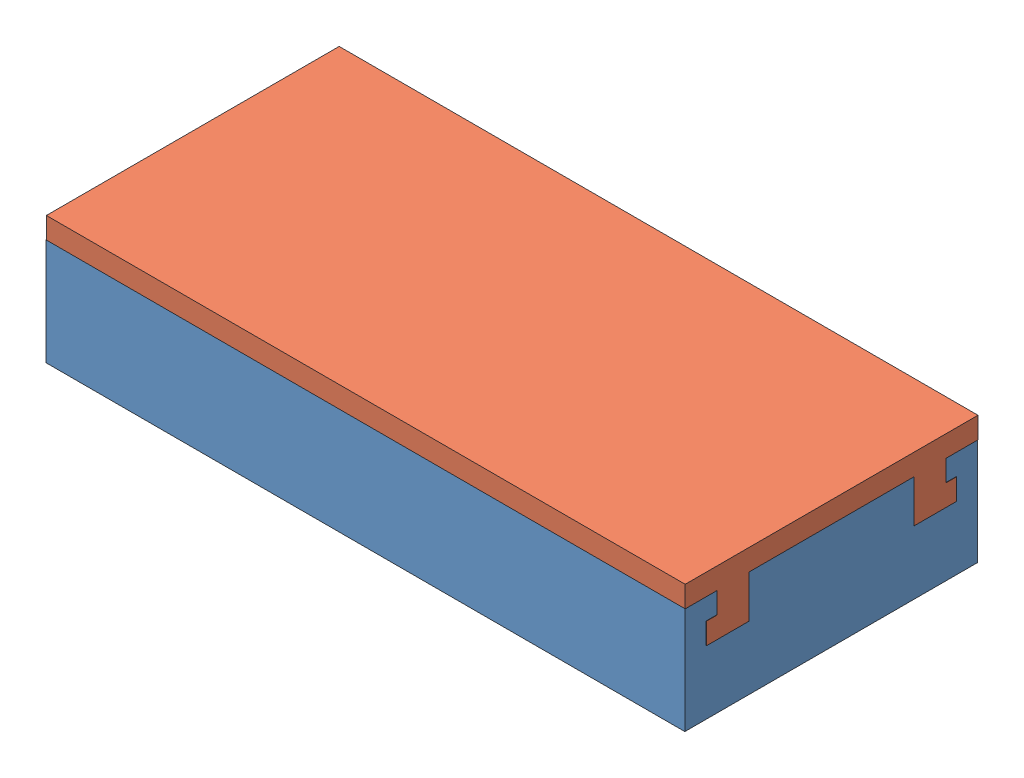
SolidWorks assembly Lighter_Asm, configuration Default. Lengths in mm.
Overall size (76.24 15.24 34.93).
2 component instances, 2 part files, 2 mates.
Components (placement in the parent):
- Lighter_housing-1: Lighter_housing [Default] at (-65.4269 20.9842 3.168) size (76.2 12.7 34.92)
- Lighter_lid-1: Lighter_lid [Default] at (-53.2421 36.2242 10.7981) x (-1 0 0) z (0 0 1) size (76.2 7.62 34.93)
Mates (geometry in assembly coordinates):
- Coincident3: coincident anti-aligned: plane of Lighter_housing-1 through (-16.9696 28.6042 -4.4335) normal (0 1 0); plane of Lighter_lid-1 through (-53.2421 28.6042 10.7981) normal (0 -1 0)
- Coincident4: coincident anti-aligned: plane of Lighter_housing-1 through (-93.1696 33.6842 24.1415) normal (0 0 -1); plane of Lighter_lid-1 through (-16.9262 28.6042 24.1415) normal (0 0 1)
